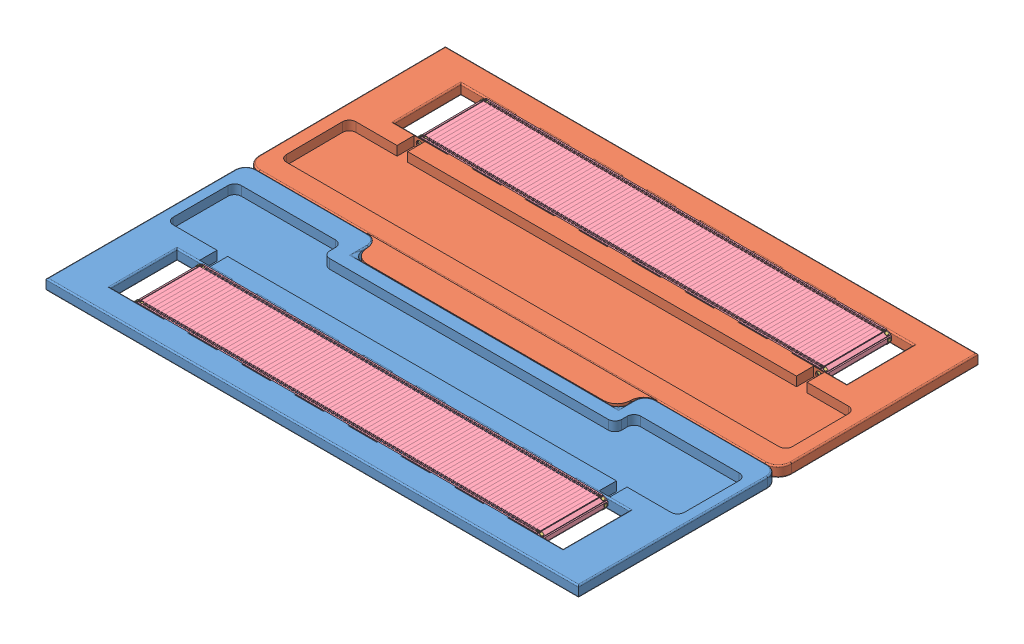
SolidWorks assembly Montagem1, configuration Valor predeterminado. Lengths in mm.
Overall size (400 11.94 300.02).
422 component instances, 5 part files, 18 mates.
Components (placement in the parent):
- LE_robot-1: LE_robot [Valor predeterminado] at (186.3434 129.0951 379.4469) size (400 8.2 150)
- LR_robot-2: LR_robot [Valor predeterminado] at (186.3434 129.6871 229.4211) x (-1 0 0) z (0 0.006964 -0.999976) size (400 8 170)
- Roller-1: Roller [Valor predeterminado] at (36.3434 134.0739 173.885) x (0 -0.006964 0.999976) z (0.000126 0.999976 0.006964) size (58 8 7.93)
- Roller-2: Roller [Valor predeterminado] at (336.3434 134.0739 173.885) x (0 -0.006964 0.999976) z (-0.866025 -0.499989 -0.003482) size (58 8 7.93)
- Roller-3: Roller [Valor predeterminado] at (336.3434 133.0951 435.0122) x (0 0 -1) z (-0.000001 1 0) size (58 8 7.93)
- Roller-4: Roller [Valor predeterminado] at (36.3434 133.0951 435.0122) x (0 0 -1) z (-0.865507 0.500897 0) size (58 8 7.93)
- EsteiraCompleta-1: EsteiraCompleta [Valor predeterminado] at (243.678 123.4337 128.0122) size (307.2 8 50)
  - esteira_caminho1-1: esteira_caminho1 [Valor predeterminado] at (-207.3346 9.6614 308)
  - esteira_borracha1-1: esteira_borracha1 [Valor predeterminado] at (89.6654 12.6614 308) size (3 1 50)
  - esteira_borracha1-9: esteira_borracha1 [Valor predeterminado] at (92.6654 12.6614 308) x (0.866026 -0.499999 0) z (0 0 1) size (3 1 50)
  - esteira_borracha1-10: esteira_borracha1 [Valor predeterminado] at (95.2635 11.1614 308) x (0.000001 -1 0) z (0 0 1) size (3 1 50)
  - esteira_borracha1-11: esteira_borracha1 [Valor predeterminado] at (95.2635 8.1614 308) x (-0.866025 -0.500001 0) z (0 0 1) size (3 1 50)
  - esteira_borracha1-12: esteira_borracha1 [Valor predeterminado] at (92.6654 6.6614 308) x (-1 0 0) z (0 0 1) size (3 1 50)
  - esteira_borracha1-13: esteira_borracha1 [Valor predeterminado] at (89.6654 6.6614 308) x (-1 0 0) z (0 0 1) size (3 1 50)
  - esteira_borracha1-14: esteira_borracha1 [Valor predeterminado] at (86.6654 6.6614 308) x (-1 0 0) z (0 0 1) size (3 1 50)
  - esteira_borracha1-15: esteira_borracha1 [Valor predeterminado] at (83.6654 6.6614 308) x (-1 0 0) z (0 0 1) size (3 1 50)
  - esteira_borracha1-16: esteira_borracha1 [Valor predeterminado] at (80.6654 6.6614 308) x (-1 0 0) z (0 0 1) size (3 1 50)
  - esteira_borracha1-17: esteira_borracha1 [Valor predeterminado] at (77.6654 6.6614 308) x (-1 0 0) z (0 0 1) size (3 1 50)
  - esteira_borracha1-18: esteira_borracha1 [Valor predeterminado] at (74.6654 6.6614 308) x (-1 0 0) z (0 0 1) size (3 1 50)
  - esteira_borracha1-19: esteira_borracha1 [Valor predeterminado] at (71.6654 6.6614 308) x (-1 0 0) z (0 0 1) size (3 1 50)
  - esteira_borracha1-20: esteira_borracha1 [Valor predeterminado] at (68.6654 6.6614 308) x (-1 0 0) z (0 0 1) size (3 1 50)
  - esteira_borracha1-21: esteira_borracha1 [Valor predeterminado] at (65.6654 6.6614 308) x (-1 0 0) z (0 0 1) size (3 1 50)
  - esteira_borracha1-22: esteira_borracha1 [Valor predeterminado] at (62.6654 6.6614 308) x (-1 0 0) z (0 0 1) size (3 1 50)
  - esteira_borracha1-23: esteira_borracha1 [Valor predeterminado] at (59.6654 6.6614 308) x (-1 0 0) z (0 0 1) size (3 1 50)
  - esteira_borracha1-24: esteira_borracha1 [Valor predeterminado] at (56.6654 6.6614 308) x (-1 0 0) z (0 0 1) size (3 1 50)
  - esteira_borracha1-25: esteira_borracha1 [Valor predeterminado] at (53.6654 6.6614 308) x (-1 0 0) z (0 0 1) size (3 1 50)
  - esteira_borracha1-26: esteira_borracha1 [Valor predeterminado] at (50.6654 6.6614 308) x (-1 0 0) z (0 0 1) size (3 1 50)
  - esteira_borracha1-27: esteira_borracha1 [Valor predeterminado] at (47.6654 6.6614 308) x (-1 0 0) z (0 0 1) size (3 1 50)
  - esteira_borracha1-28: esteira_borracha1 [Valor predeterminado] at (44.6653 6.6614 308) x (-1 0 0) z (0 0 1) size (3 1 50)
  - esteira_borracha1-29: esteira_borracha1 [Valor predeterminado] at (41.6653 6.6614 308) x (-1 0 0) z (0 0 1) size (3 1 50)
  - esteira_borracha1-30: esteira_borracha1 [Valor predeterminado] at (38.6653 6.6614 308) x (-1 0 0) z (0 0 1) size (3 1 50)
  - esteira_borracha1-31: esteira_borracha1 [Valor predeterminado] at (35.6653 6.6614 308) x (-1 0 0) z (0 0 1) size (3 1 50)
  - esteira_borracha1-32: esteira_borracha1 [Valor predeterminado] at (32.6653 6.6614 308) x (-1 0 0) z (0 0 1) size (3 1 50)
  - esteira_borracha1-33: esteira_borracha1 [Valor predeterminado] at (29.6653 6.6614 308) x (-1 0 0) z (0 0 1) size (3 1 50)
  - esteira_borracha1-34: esteira_borracha1 [Valor predeterminado] at (26.6653 6.6614 308) x (-1 0 0) z (0 0 1) size (3 1 50)
  - esteira_borracha1-35: esteira_borracha1 [Valor predeterminado] at (23.6653 6.6614 308) x (-1 0 0) z (0 0 1) size (3 1 50)
  - esteira_borracha1-36: esteira_borracha1 [Valor predeterminado] at (20.6653 6.6614 308) x (-1 0 0) z (0 0 1) size (3 1 50)
  - esteira_borracha1-37: esteira_borracha1 [Valor predeterminado] at (17.6653 6.6614 308) x (-1 0 0) z (0 0 1) size (3 1 50)
  - esteira_borracha1-38: esteira_borracha1 [Valor predeterminado] at (14.6653 6.6614 308) x (-1 0 0) z (0 0 1) size (3 1 50)
  - esteira_borracha1-39: esteira_borracha1 [Valor predeterminado] at (11.6653 6.6614 308) x (-1 0 0) z (0 0 1) size (3 1 50)
  - esteira_borracha1-40: esteira_borracha1 [Valor predeterminado] at (8.6653 6.6614 308) x (-1 0 0) z (0 0 1) size (3 1 50)
  - esteira_borracha1-41: esteira_borracha1 [Valor predeterminado] at (5.6653 6.6614 308) x (-1 0 0) z (0 0 1) size (3 1 50)
  - esteira_borracha1-42: esteira_borracha1 [Valor predeterminado] at (2.6653 6.6614 308) x (-1 0 0) z (0 0 1) size (3 1 50)
  - esteira_borracha1-43: esteira_borracha1 [Valor predeterminado] at (-0.3347 6.6614 308) x (-1 0 0) z (0 0 1) size (3 1 50)
  - esteira_borracha1-44: esteira_borracha1 [Valor predeterminado] at (-3.3347 6.6614 308) x (-1 0 0) z (0 0 1) size (3 1 50)
  - esteira_borracha1-45: esteira_borracha1 [Valor predeterminado] at (-6.3347 6.6614 308) x (-1 0 0) z (0 0 1) size (3 1 50)
  - esteira_borracha1-46: esteira_borracha1 [Valor predeterminado] at (-9.3347 6.6614 308) x (-1 0 0) z (0 0 1) size (3 1 50)
  - esteira_borracha1-47: esteira_borracha1 [Valor predeterminado] at (-12.3347 6.6614 308) x (-1 0 0) z (0 0 1) size (3 1 50)
  - esteira_borracha1-48: esteira_borracha1 [Valor predeterminado] at (-15.3347 6.6614 308) x (-1 0 0) z (0 0 1) size (3 1 50)
  - esteira_borracha1-49: esteira_borracha1 [Valor predeterminado] at (-18.3347 6.6614 308) x (-1 0 0) z (0 0 1) size (3 1 50)
  - esteira_borracha1-50: esteira_borracha1 [Valor predeterminado] at (-21.3347 6.6614 308) x (-1 0 0) z (0 0 1) size (3 1 50)
  - esteira_borracha1-51: esteira_borracha1 [Valor predeterminado] at (-24.3347 6.6614 308) x (-1 0 0) z (0 0 1) size (3 1 50)
  - esteira_borracha1-52: esteira_borracha1 [Valor predeterminado] at (-27.3347 6.6614 308) x (-1 0 0) z (0 0 1) size (3 1 50)
  - esteira_borracha1-53: esteira_borracha1 [Valor predeterminado] at (-30.3347 6.6614 308) x (-1 0 0) z (0 0 1) size (3 1 50)
  - esteira_borracha1-54: esteira_borracha1 [Valor predeterminado] at (-33.3348 6.6614 308) x (-1 0 0) z (0 0 1) size (3 1 50)
  - esteira_borracha1-55: esteira_borracha1 [Valor predeterminado] at (-36.3348 6.6614 308) x (-1 0 0) z (0 0 1) size (3 1 50)
  - esteira_borracha1-56: esteira_borracha1 [Valor predeterminado] at (-39.3348 6.6614 308) x (-1 0 0) z (0 0 1) size (3 1 50)
  - esteira_borracha1-57: esteira_borracha1 [Valor predeterminado] at (-42.3348 6.6614 308) x (-1 0 0) z (0 0 1) size (3 1 50)
  - esteira_borracha1-58: esteira_borracha1 [Valor predeterminado] at (-45.3348 6.6614 308) x (-1 0 0) z (0 0 1) size (3 1 50)
  - esteira_borracha1-59: esteira_borracha1 [Valor predeterminado] at (-48.3348 6.6614 308) x (-1 0 0) z (0 0 1) size (3 1 50)
  - esteira_borracha1-60: esteira_borracha1 [Valor predeterminado] at (-51.3348 6.6614 308) x (-1 0 0) z (0 0 1) size (3 1 50)
  - esteira_borracha1-61: esteira_borracha1 [Valor predeterminado] at (-54.3348 6.6614 308) x (-1 0 0) z (0 0 1) size (3 1 50)
  - esteira_borracha1-62: esteira_borracha1 [Valor predeterminado] at (-57.3348 6.6614 308) x (-1 0 0) z (0 0 1) size (3 1 50)
  - esteira_borracha1-63: esteira_borracha1 [Valor predeterminado] at (-60.3348 6.6614 308) x (-1 0 0) z (0 0 1) size (3 1 50)
  - esteira_borracha1-64: esteira_borracha1 [Valor predeterminado] at (-63.3348 6.6614 308) x (-1 0 0) z (0 0 1) size (3 1 50)
  - esteira_borracha1-65: esteira_borracha1 [Valor predeterminado] at (-66.3348 6.6614 308) x (-1 0 0) z (0 0 1) size (3 1 50)
  - esteira_borracha1-66: esteira_borracha1 [Valor predeterminado] at (-69.3348 6.6614 308) x (-1 0 0) z (0 0 1) size (3 1 50)
  - esteira_borracha1-67: esteira_borracha1 [Valor predeterminado] at (-72.3348 6.6614 308) x (-1 0 0) z (0 0 1) size (3 1 50)
  - esteira_borracha1-68: esteira_borracha1 [Valor predeterminado] at (-75.3348 6.6614 308) x (-1 0 0) z (0 0 1) size (3 1 50)
  - esteira_borracha1-69: esteira_borracha1 [Valor predeterminado] at (-78.3348 6.6614 308) x (-1 0 0) z (0 0 1) size (3 1 50)
  - esteira_borracha1-70: esteira_borracha1 [Valor predeterminado] at (-81.3348 6.6614 308) x (-1 0 0) z (0 0 1) size (3 1 50)
  - esteira_borracha1-71: esteira_borracha1 [Valor predeterminado] at (-84.3348 6.6614 308) x (-1 0 0) z (0 0 1) size (3 1 50)
  - esteira_borracha1-72: esteira_borracha1 [Valor predeterminado] at (-87.3348 6.6614 308) x (-1 0 0) z (0 0 1) size (3 1 50)
  - esteira_borracha1-73: esteira_borracha1 [Valor predeterminado] at (-90.3348 6.6614 308) x (-1 0 0) z (0 0 1) size (3 1 50)
  - esteira_borracha1-74: esteira_borracha1 [Valor predeterminado] at (-93.3348 6.6614 308) x (-1 0 0) z (0 0 1) size (3 1 50)
  - esteira_borracha1-75: esteira_borracha1 [Valor predeterminado] at (-96.3348 6.6614 308) x (-1 0 0) z (0 0 1) size (3 1 50)
  - esteira_borracha1-76: esteira_borracha1 [Valor predeterminado] at (-99.3348 6.6614 308) x (-1 0 0) z (0 0 1) size (3 1 50)
  - esteira_borracha1-77: esteira_borracha1 [Valor predeterminado] at (-102.3348 6.6614 308) x (-1 0 0) z (0 0 1) size (3 1 50)
  - esteira_borracha1-78: esteira_borracha1 [Valor predeterminado] at (-105.3348 6.6614 308) x (-1 0 0) z (0 0 1) size (3 1 50)
  - esteira_borracha1-79: esteira_borracha1 [Valor predeterminado] at (-108.3348 6.6614 308) x (-1 0 0) z (0 0 1) size (3 1 50)
  - esteira_borracha1-80: esteira_borracha1 [Valor predeterminado] at (-111.3348 6.6614 308) x (-1 0 0) z (0 0 1) size (3 1 50)
  - esteira_borracha1-81: esteira_borracha1 [Valor predeterminado] at (-114.3349 6.6614 308) x (-1 0 0) z (0 0 1) size (3 1 50)
  - esteira_borracha1-82: esteira_borracha1 [Valor predeterminado] at (-117.3349 6.6614 308) x (-1 0 0) z (0 0 1) size (3 1 50)
  - esteira_borracha1-83: esteira_borracha1 [Valor predeterminado] at (-120.3349 6.6614 308) x (-1 0 0) z (0 0 1) size (3 1 50)
  - esteira_borracha1-84: esteira_borracha1 [Valor predeterminado] at (-123.3349 6.6614 308) x (-1 0 0) z (0 0 1) size (3 1 50)
  - esteira_borracha1-85: esteira_borracha1 [Valor predeterminado] at (-126.3349 6.6614 308) x (-1 0 0) z (0 0 1) size (3 1 50)
  - esteira_borracha1-86: esteira_borracha1 [Valor predeterminado] at (-129.3349 6.6614 308) x (-1 0 0) z (0 0 1) size (3 1 50)
  - esteira_borracha1-87: esteira_borracha1 [Valor predeterminado] at (-132.3349 6.6614 308) x (-1 0 0) z (0 0 1) size (3 1 50)
  - esteira_borracha1-88: esteira_borracha1 [Valor predeterminado] at (-135.3349 6.6614 308) x (-1 0 0) z (0 0 1) size (3 1 50)
  - esteira_borracha1-89: esteira_borracha1 [Valor predeterminado] at (-138.3349 6.6614 308) x (-1 0 0) z (0 0 1) size (3 1 50)
  - esteira_borracha1-90: esteira_borracha1 [Valor predeterminado] at (-141.3349 6.6614 308) x (-1 0 0) z (0 0 1) size (3 1 50)
  - esteira_borracha1-91: esteira_borracha1 [Valor predeterminado] at (-144.3349 6.6614 308) x (-1 0 0) z (0 0 1) size (3 1 50)
  - esteira_borracha1-92: esteira_borracha1 [Valor predeterminado] at (-147.3349 6.6614 308) x (-1 0 0) z (0 0 1) size (3 1 50)
  - esteira_borracha1-93: esteira_borracha1 [Valor predeterminado] at (-150.3349 6.6614 308) x (-1 0 0) z (0 0 1) size (3 1 50)
  - esteira_borracha1-94: esteira_borracha1 [Valor predeterminado] at (-153.3349 6.6614 308) x (-1 0 0) z (0 0 1) size (3 1 50)
  - esteira_borracha1-95: esteira_borracha1 [Valor predeterminado] at (-156.3349 6.6614 308) x (-1 0 0) z (0 0 1) size (3 1 50)
  - esteira_borracha1-96: esteira_borracha1 [Valor predeterminado] at (-159.3349 6.6614 308) x (-1 0 0) z (0 0 1) size (3 1 50)
  - esteira_borracha1-97: esteira_borracha1 [Valor predeterminado] at (-162.3349 6.6614 308) x (-1 0 0) z (0 0 1) size (3 1 50)
  - esteira_borracha1-98: esteira_borracha1 [Valor predeterminado] at (-165.3349 6.6614 308) x (-1 0 0) z (0 0 1) size (3 1 50)
  - esteira_borracha1-99: esteira_borracha1 [Valor predeterminado] at (-168.3349 6.6614 308) x (-1 0 0) z (0 0 1) size (3 1 50)
  - esteira_borracha1-100: esteira_borracha1 [Valor predeterminado] at (-171.3349 6.6614 308) x (-1 0 0) z (0 0 1) size (3 1 50)
  - esteira_borracha1-101: esteira_borracha1 [Valor predeterminado] at (-174.3349 6.6614 308) x (-1 0 0) z (0 0 1) size (3 1 50)
  - esteira_borracha1-102: esteira_borracha1 [Valor predeterminado] at (-177.3349 6.6614 308) x (-1 0 0) z (0 0 1) size (3 1 50)
  - esteira_borracha1-103: esteira_borracha1 [Valor predeterminado] at (-180.3349 6.6614 308) x (-1 0 0) z (0 0 1) size (3 1 50)
  - esteira_borracha1-104: esteira_borracha1 [Valor predeterminado] at (-183.3349 6.6614 308) x (-1 0 0) z (0 0 1) size (3 1 50)
  - esteira_borracha1-105: esteira_borracha1 [Valor predeterminado] at (-186.3349 6.6614 308) x (-1 0 0) z (0 0 1) size (3 1 50)
  - esteira_borracha1-106: esteira_borracha1 [Valor predeterminado] at (-189.3349 6.6614 308) x (-1 0 0) z (0 0 1) size (3 1 50)
  - esteira_borracha1-107: esteira_borracha1 [Valor predeterminado] at (-192.335 6.6614 308) x (-1 0 0) z (0 0 1) size (3 1 50)
  - esteira_borracha1-108: esteira_borracha1 [Valor predeterminado] at (-195.335 6.6614 308) x (-1 0 0) z (0 0 1) size (3 1 50)
  - esteira_borracha1-109: esteira_borracha1 [Valor predeterminado] at (-198.335 6.6614 308) x (-1 0 0) z (0 0 1) size (3 1 50)
  - esteira_borracha1-110: esteira_borracha1 [Valor predeterminado] at (-201.335 6.6614 308) x (-1 0 0) z (0 0 1) size (3 1 50)
  - esteira_borracha1-111: esteira_borracha1 [Valor predeterminado] at (-204.335 6.6614 308) x (-1 0 0) z (0 0 1) size (3 1 50)
  - esteira_borracha1-112: esteira_borracha1 [Valor predeterminado] at (-207.335 6.6614 308) x (-0.865963 0.500107 0) z (0 0 1) size (3 1 50)
  - esteira_borracha1-113: esteira_borracha1 [Valor predeterminado] at (-209.9329 8.1617 308) x (0.000125 1 0) z (0 0 1) size (3 1 50)
  - esteira_borracha1-114: esteira_borracha1 [Valor predeterminado] at (-209.9325 11.1617 308) x (0.866089 0.499891 0) z (0 0 1) size (3 1 50)
  - esteira_borracha1-115: esteira_borracha1 [Valor predeterminado] at (-207.3342 12.6614 308) size (3 1 50)
  - esteira_borracha1-116: esteira_borracha1 [Valor predeterminado] at (-204.3342 12.6614 308) size (3 1 50)
  - esteira_borracha1-117: esteira_borracha1 [Valor predeterminado] at (-201.3342 12.6614 308) size (3 1 50)
  - esteira_borracha1-118: esteira_borracha1 [Valor predeterminado] at (-198.3342 12.6614 308) size (3 1 50)
  - esteira_borracha1-119: esteira_borracha1 [Valor predeterminado] at (-195.3342 12.6614 308) size (3 1 50)
  - esteira_borracha1-120: esteira_borracha1 [Valor predeterminado] at (-192.3342 12.6614 308) size (3 1 50)
  - esteira_borracha1-121: esteira_borracha1 [Valor predeterminado] at (-189.3342 12.6614 308) size (3 1 50)
  - esteira_borracha1-122: esteira_borracha1 [Valor predeterminado] at (-186.3342 12.6614 308) size (3 1 50)
  - esteira_borracha1-123: esteira_borracha1 [Valor predeterminado] at (-183.3342 12.6614 308) size (3 1 50)
  - esteira_borracha1-124: esteira_borracha1 [Valor predeterminado] at (-180.3342 12.6614 308) size (3 1 50)
  - esteira_borracha1-125: esteira_borracha1 [Valor predeterminado] at (-177.3342 12.6614 308) size (3 1 50)
  - esteira_borracha1-126: esteira_borracha1 [Valor predeterminado] at (-174.3342 12.6614 308) size (3 1 50)
  - esteira_borracha1-127: esteira_borracha1 [Valor predeterminado] at (-171.3342 12.6614 308) size (3 1 50)
  - esteira_borracha1-128: esteira_borracha1 [Valor predeterminado] at (-168.3342 12.6614 308) size (3 1 50)
  - esteira_borracha1-129: esteira_borracha1 [Valor predeterminado] at (-165.3342 12.6614 308) size (3 1 50)
  - esteira_borracha1-130: esteira_borracha1 [Valor predeterminado] at (-162.3342 12.6614 308) size (3 1 50)
  - esteira_borracha1-131: esteira_borracha1 [Valor predeterminado] at (-159.3342 12.6614 308) size (3 1 50)
  - esteira_borracha1-132: esteira_borracha1 [Valor predeterminado] at (-156.3342 12.6614 308) size (3 1 50)
  - esteira_borracha1-133: esteira_borracha1 [Valor predeterminado] at (-153.3341 12.6614 308) size (3 1 50)
  - esteira_borracha1-134: esteira_borracha1 [Valor predeterminado] at (-150.3341 12.6614 308) size (3 1 50)
  - esteira_borracha1-135: esteira_borracha1 [Valor predeterminado] at (-147.3341 12.6614 308) size (3 1 50)
  - esteira_borracha1-136: esteira_borracha1 [Valor predeterminado] at (-144.3341 12.6614 308) size (3 1 50)
  - esteira_borracha1-137: esteira_borracha1 [Valor predeterminado] at (-141.3341 12.6614 308) size (3 1 50)
  - esteira_borracha1-138: esteira_borracha1 [Valor predeterminado] at (-138.3341 12.6614 308) size (3 1 50)
  - esteira_borracha1-139: esteira_borracha1 [Valor predeterminado] at (-135.3341 12.6614 308) size (3 1 50)
  - esteira_borracha1-140: esteira_borracha1 [Valor predeterminado] at (-132.3341 12.6614 308) size (3 1 50)
  - esteira_borracha1-141: esteira_borracha1 [Valor predeterminado] at (-129.3341 12.6614 308) size (3 1 50)
  - esteira_borracha1-142: esteira_borracha1 [Valor predeterminado] at (-126.3341 12.6614 308) size (3 1 50)
  - esteira_borracha1-143: esteira_borracha1 [Valor predeterminado] at (-123.3341 12.6614 308) size (3 1 50)
  - esteira_borracha1-144: esteira_borracha1 [Valor predeterminado] at (-120.3341 12.6614 308) size (3 1 50)
  - esteira_borracha1-145: esteira_borracha1 [Valor predeterminado] at (-117.3341 12.6614 308) size (3 1 50)
  - esteira_borracha1-146: esteira_borracha1 [Valor predeterminado] at (-114.3341 12.6614 308) size (3 1 50)
  - esteira_borracha1-147: esteira_borracha1 [Valor predeterminado] at (-111.3341 12.6614 308) size (3 1 50)
  - esteira_borracha1-148: esteira_borracha1 [Valor predeterminado] at (-108.3341 12.6614 308) size (3 1 50)
  - esteira_borracha1-149: esteira_borracha1 [Valor predeterminado] at (-105.3341 12.6614 308) size (3 1 50)
  - esteira_borracha1-150: esteira_borracha1 [Valor predeterminado] at (-102.3341 12.6614 308) size (3 1 50)
  - esteira_borracha1-151: esteira_borracha1 [Valor predeterminado] at (-99.3341 12.6614 308) size (3 1 50)
  - esteira_borracha1-152: esteira_borracha1 [Valor predeterminado] at (-96.3341 12.6614 308) size (3 1 50)
  - esteira_borracha1-153: esteira_borracha1 [Valor predeterminado] at (-93.3341 12.6614 308) size (3 1 50)
  - esteira_borracha1-154: esteira_borracha1 [Valor predeterminado] at (-90.3341 12.6614 308) size (3 1 50)
  - esteira_borracha1-155: esteira_borracha1 [Valor predeterminado] at (-87.3341 12.6614 308) size (3 1 50)
  - esteira_borracha1-156: esteira_borracha1 [Valor predeterminado] at (-84.3341 12.6614 308) size (3 1 50)
  - esteira_borracha1-157: esteira_borracha1 [Valor predeterminado] at (-81.3341 12.6614 308) size (3 1 50)
  - esteira_borracha1-158: esteira_borracha1 [Valor predeterminado] at (-78.3341 12.6614 308) size (3 1 50)
  - esteira_borracha1-159: esteira_borracha1 [Valor predeterminado] at (-75.3341 12.6614 308) size (3 1 50)
  - esteira_borracha1-160: esteira_borracha1 [Valor predeterminado] at (-72.334 12.6614 308) size (3 1 50)
  - esteira_borracha1-161: esteira_borracha1 [Valor predeterminado] at (-69.334 12.6614 308) size (3 1 50)
  - esteira_borracha1-164: esteira_borracha1 [Valor predeterminado] at (-66.334 12.6614 308) size (3 1 50)
  - esteira_borracha1-165: esteira_borracha1 [Valor predeterminado] at (-63.334 12.6614 308) size (3 1 50)
  - esteira_borracha1-166: esteira_borracha1 [Valor predeterminado] at (-60.334 12.6614 308) size (3 1 50)
  - esteira_borracha1-167: esteira_borracha1 [Valor predeterminado] at (-57.334 12.6614 308) size (3 1 50)
  - esteira_borracha1-168: esteira_borracha1 [Valor predeterminado] at (-54.334 12.6614 308) size (3 1 50)
  - esteira_borracha1-169: esteira_borracha1 [Valor predeterminado] at (-51.334 12.6614 308) size (3 1 50)
  - esteira_borracha1-170: esteira_borracha1 [Valor predeterminado] at (-48.334 12.6614 308) size (3 1 50)
  - esteira_borracha1-171: esteira_borracha1 [Valor predeterminado] at (-45.334 12.6614 308) size (3 1 50)
  - esteira_borracha1-172: esteira_borracha1 [Valor predeterminado] at (-42.334 12.6614 308) size (3 1 50)
  - esteira_borracha1-173: esteira_borracha1 [Valor predeterminado] at (-39.334 12.6614 308) size (3 1 50)
  - esteira_borracha1-174: esteira_borracha1 [Valor predeterminado] at (-36.334 12.6614 308) size (3 1 50)
  - esteira_borracha1-175: esteira_borracha1 [Valor predeterminado] at (-33.334 12.6614 308) size (3 1 50)
  - esteira_borracha1-176: esteira_borracha1 [Valor predeterminado] at (-30.334 12.6614 308) size (3 1 50)
  - esteira_borracha1-177: esteira_borracha1 [Valor predeterminado] at (-27.334 12.6614 308) size (3 1 50)
  - esteira_borracha1-178: esteira_borracha1 [Valor predeterminado] at (-24.334 12.6614 308) size (3 1 50)
  - esteira_borracha1-179: esteira_borracha1 [Valor predeterminado] at (-21.334 12.6614 308) size (3 1 50)
  - esteira_borracha1-180: esteira_borracha1 [Valor predeterminado] at (-18.334 12.6614 308) size (3 1 50)
  - esteira_borracha1-181: esteira_borracha1 [Valor predeterminado] at (-15.334 12.6614 308) size (3 1 50)
  - esteira_borracha1-182: esteira_borracha1 [Valor predeterminado] at (-12.334 12.6614 308) size (3 1 50)
  - esteira_borracha1-183: esteira_borracha1 [Valor predeterminado] at (-9.334 12.6614 308) size (3 1 50)
  - esteira_borracha1-184: esteira_borracha1 [Valor predeterminado] at (-6.334 12.6614 308) size (3 1 50)
  - esteira_borracha1-185: esteira_borracha1 [Valor predeterminado] at (-3.334 12.6614 308) size (3 1 50)
  - esteira_borracha1-186: esteira_borracha1 [Valor predeterminado] at (-0.334 12.6614 308) size (3 1 50)
  - esteira_borracha1-187: esteira_borracha1 [Valor predeterminado] at (2.666 12.6614 308) size (3 1 50)
  - esteira_borracha1-188: esteira_borracha1 [Valor predeterminado] at (5.6661 12.6614 308) size (3 1 50)
  - esteira_borracha1-189: esteira_borracha1 [Valor predeterminado] at (8.6661 12.6614 308) size (3 1 50)
  - esteira_borracha1-190: esteira_borracha1 [Valor predeterminado] at (11.6661 12.6614 308) size (3 1 50)
  - esteira_borracha1-191: esteira_borracha1 [Valor predeterminado] at (14.6661 12.6614 308) size (3 1 50)
  - esteira_borracha1-192: esteira_borracha1 [Valor predeterminado] at (17.6661 12.6614 308) size (3 1 50)
  - esteira_borracha1-193: esteira_borracha1 [Valor predeterminado] at (20.6661 12.6614 308) size (3 1 50)
  - esteira_borracha1-194: esteira_borracha1 [Valor predeterminado] at (23.6661 12.6614 308) size (3 1 50)
  - esteira_borracha1-195: esteira_borracha1 [Valor predeterminado] at (26.6661 12.6614 308) size (3 1 50)
  - esteira_borracha1-196: esteira_borracha1 [Valor predeterminado] at (29.6661 12.6614 308) size (3 1 50)
  - esteira_borracha1-197: esteira_borracha1 [Valor predeterminado] at (32.6661 12.6614 308) size (3 1 50)
  - esteira_borracha1-198: esteira_borracha1 [Valor predeterminado] at (35.6661 12.6614 308) size (3 1 50)
  - esteira_borracha1-199: esteira_borracha1 [Valor predeterminado] at (38.6661 12.6614 308) size (3 1 50)
  - esteira_borracha1-200: esteira_borracha1 [Valor predeterminado] at (41.6661 12.6614 308) size (3 1 50)
  - esteira_borracha1-201: esteira_borracha1 [Valor predeterminado] at (44.6661 12.6614 308) size (3 1 50)
  - esteira_borracha1-202: esteira_borracha1 [Valor predeterminado] at (47.6661 12.6614 308) size (3 1 50)
  - esteira_borracha1-203: esteira_borracha1 [Valor predeterminado] at (50.6661 12.6614 308) size (3 1 50)
  - esteira_borracha1-204: esteira_borracha1 [Valor predeterminado] at (53.6661 12.6614 308) size (3 1 50)
  - esteira_borracha1-205: esteira_borracha1 [Valor predeterminado] at (56.6661 12.6614 308) size (3 1 50)
  - esteira_borracha1-206: esteira_borracha1 [Valor predeterminado] at (59.6661 12.6614 308) size (3 1 50)
  - esteira_borracha1-207: esteira_borracha1 [Valor predeterminado] at (62.6661 12.6614 308) size (3 1 50)
  - esteira_borracha1-208: esteira_borracha1 [Valor predeterminado] at (65.6661 12.6614 308) size (3 1 50)
  - esteira_borracha1-209: esteira_borracha1 [Valor predeterminado] at (68.6661 12.6614 308) size (3 1 50)
  - esteira_borracha1-210: esteira_borracha1 [Valor predeterminado] at (71.6661 12.6614 308) size (3 1 50)
  - esteira_borracha1-211: esteira_borracha1 [Valor predeterminado] at (74.6661 12.6614 308) size (3 1 50)
  - esteira_borracha1-212: esteira_borracha1 [Valor predeterminado] at (77.6661 12.6614 308) size (3 1 50)
  - esteira_borracha1-213: esteira_borracha1 [Valor predeterminado] at (80.6661 12.6614 308) size (3 1 50)
  - esteira_borracha1-214: esteira_borracha1 [Valor predeterminado] at (83.6661 12.6614 308) size (3 1 50)
  - esteira_borracha1-215: esteira_borracha1 [Valor predeterminado] at (86.6662 12.6614 308) size (3 1 50)
- EsteiraCompleta-2: EsteiraCompleta [Valor predeterminado] at (243.678 126.2164 -85.176) x (1 0 0) z (0 -0.006964 0.999976) size (307.2 8 50)
  - esteira_caminho1-1: esteira_caminho1 [Valor predeterminado] at (-207.3346 9.6614 308)
  - esteira_borracha1-1: esteira_borracha1 [Valor predeterminado] at (89.6654 12.6614 308) size (3 1 50)
  - esteira_borracha1-9: esteira_borracha1 [Valor predeterminado] at (92.6654 12.6614 308) x (0.866026 -0.499999 0) z (0 0 1) size (3 1 50)
  - esteira_borracha1-10: esteira_borracha1 [Valor predeterminado] at (95.2635 11.1614 308) x (0.000001 -1 0) z (0 0 1) size (3 1 50)
  - esteira_borracha1-11: esteira_borracha1 [Valor predeterminado] at (95.2635 8.1614 308) x (-0.866025 -0.500001 0) z (0 0 1) size (3 1 50)
  - esteira_borracha1-12: esteira_borracha1 [Valor predeterminado] at (92.6654 6.6614 308) x (-1 0 0) z (0 0 1) size (3 1 50)
  - esteira_borracha1-13: esteira_borracha1 [Valor predeterminado] at (89.6654 6.6614 308) x (-1 0 0) z (0 0 1) size (3 1 50)
  - esteira_borracha1-14: esteira_borracha1 [Valor predeterminado] at (86.6654 6.6614 308) x (-1 0 0) z (0 0 1) size (3 1 50)
  - esteira_borracha1-15: esteira_borracha1 [Valor predeterminado] at (83.6654 6.6614 308) x (-1 0 0) z (0 0 1) size (3 1 50)
  - esteira_borracha1-16: esteira_borracha1 [Valor predeterminado] at (80.6654 6.6614 308) x (-1 0 0) z (0 0 1) size (3 1 50)
  - esteira_borracha1-17: esteira_borracha1 [Valor predeterminado] at (77.6654 6.6614 308) x (-1 0 0) z (0 0 1) size (3 1 50)
  - esteira_borracha1-18: esteira_borracha1 [Valor predeterminado] at (74.6654 6.6614 308) x (-1 0 0) z (0 0 1) size (3 1 50)
  - esteira_borracha1-19: esteira_borracha1 [Valor predeterminado] at (71.6654 6.6614 308) x (-1 0 0) z (0 0 1) size (3 1 50)
  - esteira_borracha1-20: esteira_borracha1 [Valor predeterminado] at (68.6654 6.6614 308) x (-1 0 0) z (0 0 1) size (3 1 50)
  - esteira_borracha1-21: esteira_borracha1 [Valor predeterminado] at (65.6654 6.6614 308) x (-1 0 0) z (0 0 1) size (3 1 50)
  - esteira_borracha1-22: esteira_borracha1 [Valor predeterminado] at (62.6654 6.6614 308) x (-1 0 0) z (0 0 1) size (3 1 50)
  - esteira_borracha1-23: esteira_borracha1 [Valor predeterminado] at (59.6654 6.6614 308) x (-1 0 0) z (0 0 1) size (3 1 50)
  - esteira_borracha1-24: esteira_borracha1 [Valor predeterminado] at (56.6654 6.6614 308) x (-1 0 0) z (0 0 1) size (3 1 50)
  - esteira_borracha1-25: esteira_borracha1 [Valor predeterminado] at (53.6654 6.6614 308) x (-1 0 0) z (0 0 1) size (3 1 50)
  - esteira_borracha1-26: esteira_borracha1 [Valor predeterminado] at (50.6654 6.6614 308) x (-1 0 0) z (0 0 1) size (3 1 50)
  - esteira_borracha1-27: esteira_borracha1 [Valor predeterminado] at (47.6654 6.6614 308) x (-1 0 0) z (0 0 1) size (3 1 50)
  - esteira_borracha1-28: esteira_borracha1 [Valor predeterminado] at (44.6653 6.6614 308) x (-1 0 0) z (0 0 1) size (3 1 50)
  - esteira_borracha1-29: esteira_borracha1 [Valor predeterminado] at (41.6653 6.6614 308) x (-1 0 0) z (0 0 1) size (3 1 50)
  - esteira_borracha1-30: esteira_borracha1 [Valor predeterminado] at (38.6653 6.6614 308) x (-1 0 0) z (0 0 1) size (3 1 50)
  - esteira_borracha1-31: esteira_borracha1 [Valor predeterminado] at (35.6653 6.6614 308) x (-1 0 0) z (0 0 1) size (3 1 50)
  - esteira_borracha1-32: esteira_borracha1 [Valor predeterminado] at (32.6653 6.6614 308) x (-1 0 0) z (0 0 1) size (3 1 50)
  - esteira_borracha1-33: esteira_borracha1 [Valor predeterminado] at (29.6653 6.6614 308) x (-1 0 0) z (0 0 1) size (3 1 50)
  - esteira_borracha1-34: esteira_borracha1 [Valor predeterminado] at (26.6653 6.6614 308) x (-1 0 0) z (0 0 1) size (3 1 50)
  - esteira_borracha1-35: esteira_borracha1 [Valor predeterminado] at (23.6653 6.6614 308) x (-1 0 0) z (0 0 1) size (3 1 50)
  - esteira_borracha1-36: esteira_borracha1 [Valor predeterminado] at (20.6653 6.6614 308) x (-1 0 0) z (0 0 1) size (3 1 50)
  - esteira_borracha1-37: esteira_borracha1 [Valor predeterminado] at (17.6653 6.6614 308) x (-1 0 0) z (0 0 1) size (3 1 50)
  - esteira_borracha1-38: esteira_borracha1 [Valor predeterminado] at (14.6653 6.6614 308) x (-1 0 0) z (0 0 1) size (3 1 50)
  - esteira_borracha1-39: esteira_borracha1 [Valor predeterminado] at (11.6653 6.6614 308) x (-1 0 0) z (0 0 1) size (3 1 50)
  - esteira_borracha1-40: esteira_borracha1 [Valor predeterminado] at (8.6653 6.6614 308) x (-1 0 0) z (0 0 1) size (3 1 50)
  - esteira_borracha1-41: esteira_borracha1 [Valor predeterminado] at (5.6653 6.6614 308) x (-1 0 0) z (0 0 1) size (3 1 50)
  - esteira_borracha1-42: esteira_borracha1 [Valor predeterminado] at (2.6653 6.6614 308) x (-1 0 0) z (0 0 1) size (3 1 50)
  - esteira_borracha1-43: esteira_borracha1 [Valor predeterminado] at (-0.3347 6.6614 308) x (-1 0 0) z (0 0 1) size (3 1 50)
  - esteira_borracha1-44: esteira_borracha1 [Valor predeterminado] at (-3.3347 6.6614 308) x (-1 0 0) z (0 0 1) size (3 1 50)
  - esteira_borracha1-45: esteira_borracha1 [Valor predeterminado] at (-6.3347 6.6614 308) x (-1 0 0) z (0 0 1) size (3 1 50)
  - esteira_borracha1-46: esteira_borracha1 [Valor predeterminado] at (-9.3347 6.6614 308) x (-1 0 0) z (0 0 1) size (3 1 50)
  - esteira_borracha1-47: esteira_borracha1 [Valor predeterminado] at (-12.3347 6.6614 308) x (-1 0 0) z (0 0 1) size (3 1 50)
  - esteira_borracha1-48: esteira_borracha1 [Valor predeterminado] at (-15.3347 6.6614 308) x (-1 0 0) z (0 0 1) size (3 1 50)
  - esteira_borracha1-49: esteira_borracha1 [Valor predeterminado] at (-18.3347 6.6614 308) x (-1 0 0) z (0 0 1) size (3 1 50)
  - esteira_borracha1-50: esteira_borracha1 [Valor predeterminado] at (-21.3347 6.6614 308) x (-1 0 0) z (0 0 1) size (3 1 50)
  - esteira_borracha1-51: esteira_borracha1 [Valor predeterminado] at (-24.3347 6.6614 308) x (-1 0 0) z (0 0 1) size (3 1 50)
  - esteira_borracha1-52: esteira_borracha1 [Valor predeterminado] at (-27.3347 6.6614 308) x (-1 0 0) z (0 0 1) size (3 1 50)
  - esteira_borracha1-53: esteira_borracha1 [Valor predeterminado] at (-30.3347 6.6614 308) x (-1 0 0) z (0 0 1) size (3 1 50)
  - esteira_borracha1-54: esteira_borracha1 [Valor predeterminado] at (-33.3348 6.6614 308) x (-1 0 0) z (0 0 1) size (3 1 50)
  - esteira_borracha1-55: esteira_borracha1 [Valor predeterminado] at (-36.3348 6.6614 308) x (-1 0 0) z (0 0 1) size (3 1 50)
  - esteira_borracha1-56: esteira_borracha1 [Valor predeterminado] at (-39.3348 6.6614 308) x (-1 0 0) z (0 0 1) size (3 1 50)
  - esteira_borracha1-57: esteira_borracha1 [Valor predeterminado] at (-42.3348 6.6614 308) x (-1 0 0) z (0 0 1) size (3 1 50)
  - esteira_borracha1-58: esteira_borracha1 [Valor predeterminado] at (-45.3348 6.6614 308) x (-1 0 0) z (0 0 1) size (3 1 50)
  - esteira_borracha1-59: esteira_borracha1 [Valor predeterminado] at (-48.3348 6.6614 308) x (-1 0 0) z (0 0 1) size (3 1 50)
  - esteira_borracha1-60: esteira_borracha1 [Valor predeterminado] at (-51.3348 6.6614 308) x (-1 0 0) z (0 0 1) size (3 1 50)
  - esteira_borracha1-61: esteira_borracha1 [Valor predeterminado] at (-54.3348 6.6614 308) x (-1 0 0) z (0 0 1) size (3 1 50)
  - esteira_borracha1-62: esteira_borracha1 [Valor predeterminado] at (-57.3348 6.6614 308) x (-1 0 0) z (0 0 1) size (3 1 50)
  - esteira_borracha1-63: esteira_borracha1 [Valor predeterminado] at (-60.3348 6.6614 308) x (-1 0 0) z (0 0 1) size (3 1 50)
  - esteira_borracha1-64: esteira_borracha1 [Valor predeterminado] at (-63.3348 6.6614 308) x (-1 0 0) z (0 0 1) size (3 1 50)
  - esteira_borracha1-65: esteira_borracha1 [Valor predeterminado] at (-66.3348 6.6614 308) x (-1 0 0) z (0 0 1) size (3 1 50)
  - esteira_borracha1-66: esteira_borracha1 [Valor predeterminado] at (-69.3348 6.6614 308) x (-1 0 0) z (0 0 1) size (3 1 50)
  - esteira_borracha1-67: esteira_borracha1 [Valor predeterminado] at (-72.3348 6.6614 308) x (-1 0 0) z (0 0 1) size (3 1 50)
  - esteira_borracha1-68: esteira_borracha1 [Valor predeterminado] at (-75.3348 6.6614 308) x (-1 0 0) z (0 0 1) size (3 1 50)
  - esteira_borracha1-69: esteira_borracha1 [Valor predeterminado] at (-78.3348 6.6614 308) x (-1 0 0) z (0 0 1) size (3 1 50)
  - esteira_borracha1-70: esteira_borracha1 [Valor predeterminado] at (-81.3348 6.6614 308) x (-1 0 0) z (0 0 1) size (3 1 50)
  - esteira_borracha1-71: esteira_borracha1 [Valor predeterminado] at (-84.3348 6.6614 308) x (-1 0 0) z (0 0 1) size (3 1 50)
  - esteira_borracha1-72: esteira_borracha1 [Valor predeterminado] at (-87.3348 6.6614 308) x (-1 0 0) z (0 0 1) size (3 1 50)
  - esteira_borracha1-73: esteira_borracha1 [Valor predeterminado] at (-90.3348 6.6614 308) x (-1 0 0) z (0 0 1) size (3 1 50)
  - esteira_borracha1-74: esteira_borracha1 [Valor predeterminado] at (-93.3348 6.6614 308) x (-1 0 0) z (0 0 1) size (3 1 50)
  - esteira_borracha1-75: esteira_borracha1 [Valor predeterminado] at (-96.3348 6.6614 308) x (-1 0 0) z (0 0 1) size (3 1 50)
  - esteira_borracha1-76: esteira_borracha1 [Valor predeterminado] at (-99.3348 6.6614 308) x (-1 0 0) z (0 0 1) size (3 1 50)
  - esteira_borracha1-77: esteira_borracha1 [Valor predeterminado] at (-102.3348 6.6614 308) x (-1 0 0) z (0 0 1) size (3 1 50)
  - esteira_borracha1-78: esteira_borracha1 [Valor predeterminado] at (-105.3348 6.6614 308) x (-1 0 0) z (0 0 1) size (3 1 50)
  - esteira_borracha1-79: esteira_borracha1 [Valor predeterminado] at (-108.3348 6.6614 308) x (-1 0 0) z (0 0 1) size (3 1 50)
  - esteira_borracha1-80: esteira_borracha1 [Valor predeterminado] at (-111.3348 6.6614 308) x (-1 0 0) z (0 0 1) size (3 1 50)
  - esteira_borracha1-81: esteira_borracha1 [Valor predeterminado] at (-114.3349 6.6614 308) x (-1 0 0) z (0 0 1) size (3 1 50)
  - esteira_borracha1-82: esteira_borracha1 [Valor predeterminado] at (-117.3349 6.6614 308) x (-1 0 0) z (0 0 1) size (3 1 50)
  - esteira_borracha1-83: esteira_borracha1 [Valor predeterminado] at (-120.3349 6.6614 308) x (-1 0 0) z (0 0 1) size (3 1 50)
  - esteira_borracha1-84: esteira_borracha1 [Valor predeterminado] at (-123.3349 6.6614 308) x (-1 0 0) z (0 0 1) size (3 1 50)
  - esteira_borracha1-85: esteira_borracha1 [Valor predeterminado] at (-126.3349 6.6614 308) x (-1 0 0) z (0 0 1) size (3 1 50)
  - esteira_borracha1-86: esteira_borracha1 [Valor predeterminado] at (-129.3349 6.6614 308) x (-1 0 0) z (0 0 1) size (3 1 50)
  - esteira_borracha1-87: esteira_borracha1 [Valor predeterminado] at (-132.3349 6.6614 308) x (-1 0 0) z (0 0 1) size (3 1 50)
  - esteira_borracha1-88: esteira_borracha1 [Valor predeterminado] at (-135.3349 6.6614 308) x (-1 0 0) z (0 0 1) size (3 1 50)
  - esteira_borracha1-89: esteira_borracha1 [Valor predeterminado] at (-138.3349 6.6614 308) x (-1 0 0) z (0 0 1) size (3 1 50)
  - esteira_borracha1-90: esteira_borracha1 [Valor predeterminado] at (-141.3349 6.6614 308) x (-1 0 0) z (0 0 1) size (3 1 50)
  - esteira_borracha1-91: esteira_borracha1 [Valor predeterminado] at (-144.3349 6.6614 308) x (-1 0 0) z (0 0 1) size (3 1 50)
  - esteira_borracha1-92: esteira_borracha1 [Valor predeterminado] at (-147.3349 6.6614 308) x (-1 0 0) z (0 0 1) size (3 1 50)
  - esteira_borracha1-93: esteira_borracha1 [Valor predeterminado] at (-150.3349 6.6614 308) x (-1 0 0) z (0 0 1) size (3 1 50)
  - esteira_borracha1-94: esteira_borracha1 [Valor predeterminado] at (-153.3349 6.6614 308) x (-1 0 0) z (0 0 1) size (3 1 50)
  - esteira_borracha1-95: esteira_borracha1 [Valor predeterminado] at (-156.3349 6.6614 308) x (-1 0 0) z (0 0 1) size (3 1 50)
  - esteira_borracha1-96: esteira_borracha1 [Valor predeterminado] at (-159.3349 6.6614 308) x (-1 0 0) z (0 0 1) size (3 1 50)
  - esteira_borracha1-97: esteira_borracha1 [Valor predeterminado] at (-162.3349 6.6614 308) x (-1 0 0) z (0 0 1) size (3 1 50)
  - esteira_borracha1-98: esteira_borracha1 [Valor predeterminado] at (-165.3349 6.6614 308) x (-1 0 0) z (0 0 1) size (3 1 50)
  - esteira_borracha1-99: esteira_borracha1 [Valor predeterminado] at (-168.3349 6.6614 308) x (-1 0 0) z (0 0 1) size (3 1 50)
  - esteira_borracha1-100: esteira_borracha1 [Valor predeterminado] at (-171.3349 6.6614 308) x (-1 0 0) z (0 0 1) size (3 1 50)
  - esteira_borracha1-101: esteira_borracha1 [Valor predeterminado] at (-174.3349 6.6614 308) x (-1 0 0) z (0 0 1) size (3 1 50)
  - esteira_borracha1-102: esteira_borracha1 [Valor predeterminado] at (-177.3349 6.6614 308) x (-1 0 0) z (0 0 1) size (3 1 50)
  - esteira_borracha1-103: esteira_borracha1 [Valor predeterminado] at (-180.3349 6.6614 308) x (-1 0 0) z (0 0 1) size (3 1 50)
  - esteira_borracha1-104: esteira_borracha1 [Valor predeterminado] at (-183.3349 6.6614 308) x (-1 0 0) z (0 0 1) size (3 1 50)
  - esteira_borracha1-105: esteira_borracha1 [Valor predeterminado] at (-186.3349 6.6614 308) x (-1 0 0) z (0 0 1) size (3 1 50)
  - esteira_borracha1-106: esteira_borracha1 [Valor predeterminado] at (-189.3349 6.6614 308) x (-1 0 0) z (0 0 1) size (3 1 50)
  - esteira_borracha1-107: esteira_borracha1 [Valor predeterminado] at (-192.335 6.6614 308) x (-1 0 0) z (0 0 1) size (3 1 50)
  - esteira_borracha1-108: esteira_borracha1 [Valor predeterminado] at (-195.335 6.6614 308) x (-1 0 0) z (0 0 1) size (3 1 50)
  - esteira_borracha1-109: esteira_borracha1 [Valor predeterminado] at (-198.335 6.6614 308) x (-1 0 0) z (0 0 1) size (3 1 50)
  - esteira_borracha1-110: esteira_borracha1 [Valor predeterminado] at (-201.335 6.6614 308) x (-1 0 0) z (0 0 1) size (3 1 50)
  - esteira_borracha1-111: esteira_borracha1 [Valor predeterminado] at (-204.335 6.6614 308) x (-1 0 0) z (0 0 1) size (3 1 50)
  - esteira_borracha1-112: esteira_borracha1 [Valor predeterminado] at (-207.335 6.6614 308) x (-0.865963 0.500107 0) z (0 0 1) size (3 1 50)
  - esteira_borracha1-113: esteira_borracha1 [Valor predeterminado] at (-209.9329 8.1617 308) x (0.000125 1 0) z (0 0 1) size (3 1 50)
  - esteira_borracha1-114: esteira_borracha1 [Valor predeterminado] at (-209.9325 11.1617 308) x (0.866089 0.499891 0) z (0 0 1) size (3 1 50)
  - esteira_borracha1-115: esteira_borracha1 [Valor predeterminado] at (-207.3342 12.6614 308) size (3 1 50)
  - esteira_borracha1-116: esteira_borracha1 [Valor predeterminado] at (-204.3342 12.6614 308) size (3 1 50)
  - esteira_borracha1-117: esteira_borracha1 [Valor predeterminado] at (-201.3342 12.6614 308) size (3 1 50)
  - esteira_borracha1-118: esteira_borracha1 [Valor predeterminado] at (-198.3342 12.6614 308) size (3 1 50)
  - esteira_borracha1-119: esteira_borracha1 [Valor predeterminado] at (-195.3342 12.6614 308) size (3 1 50)
  - esteira_borracha1-120: esteira_borracha1 [Valor predeterminado] at (-192.3342 12.6614 308) size (3 1 50)
  - esteira_borracha1-121: esteira_borracha1 [Valor predeterminado] at (-189.3342 12.6614 308) size (3 1 50)
  - esteira_borracha1-122: esteira_borracha1 [Valor predeterminado] at (-186.3342 12.6614 308) size (3 1 50)
  - esteira_borracha1-123: esteira_borracha1 [Valor predeterminado] at (-183.3342 12.6614 308) size (3 1 50)
  - esteira_borracha1-124: esteira_borracha1 [Valor predeterminado] at (-180.3342 12.6614 308) size (3 1 50)
  - esteira_borracha1-125: esteira_borracha1 [Valor predeterminado] at (-177.3342 12.6614 308) size (3 1 50)
  - esteira_borracha1-126: esteira_borracha1 [Valor predeterminado] at (-174.3342 12.6614 308) size (3 1 50)
  - esteira_borracha1-127: esteira_borracha1 [Valor predeterminado] at (-171.3342 12.6614 308) size (3 1 50)
  - esteira_borracha1-128: esteira_borracha1 [Valor predeterminado] at (-168.3342 12.6614 308) size (3 1 50)
  - esteira_borracha1-129: esteira_borracha1 [Valor predeterminado] at (-165.3342 12.6614 308) size (3 1 50)
  - esteira_borracha1-130: esteira_borracha1 [Valor predeterminado] at (-162.3342 12.6614 308) size (3 1 50)
  - esteira_borracha1-131: esteira_borracha1 [Valor predeterminado] at (-159.3342 12.6614 308) size (3 1 50)
  - esteira_borracha1-132: esteira_borracha1 [Valor predeterminado] at (-156.3342 12.6614 308) size (3 1 50)
  - esteira_borracha1-133: esteira_borracha1 [Valor predeterminado] at (-153.3341 12.6614 308) size (3 1 50)
  - esteira_borracha1-134: esteira_borracha1 [Valor predeterminado] at (-150.3341 12.6614 308) size (3 1 50)
  - esteira_borracha1-135: esteira_borracha1 [Valor predeterminado] at (-147.3341 12.6614 308) size (3 1 50)
  - esteira_borracha1-136: esteira_borracha1 [Valor predeterminado] at (-144.3341 12.6614 308) size (3 1 50)
  - esteira_borracha1-137: esteira_borracha1 [Valor predeterminado] at (-141.3341 12.6614 308) size (3 1 50)
  - esteira_borracha1-138: esteira_borracha1 [Valor predeterminado] at (-138.3341 12.6614 308) size (3 1 50)
  - esteira_borracha1-139: esteira_borracha1 [Valor predeterminado] at (-135.3341 12.6614 308) size (3 1 50)
  - esteira_borracha1-140: esteira_borracha1 [Valor predeterminado] at (-132.3341 12.6614 308) size (3 1 50)
  - esteira_borracha1-141: esteira_borracha1 [Valor predeterminado] at (-129.3341 12.6614 308) size (3 1 50)
  - esteira_borracha1-142: esteira_borracha1 [Valor predeterminado] at (-126.3341 12.6614 308) size (3 1 50)
  - esteira_borracha1-143: esteira_borracha1 [Valor predeterminado] at (-123.3341 12.6614 308) size (3 1 50)
  - esteira_borracha1-144: esteira_borracha1 [Valor predeterminado] at (-120.3341 12.6614 308) size (3 1 50)
  - esteira_borracha1-145: esteira_borracha1 [Valor predeterminado] at (-117.3341 12.6614 308) size (3 1 50)
  - esteira_borracha1-146: esteira_borracha1 [Valor predeterminado] at (-114.3341 12.6614 308) size (3 1 50)
  - esteira_borracha1-147: esteira_borracha1 [Valor predeterminado] at (-111.3341 12.6614 308) size (3 1 50)
  - esteira_borracha1-148: esteira_borracha1 [Valor predeterminado] at (-108.3341 12.6614 308) size (3 1 50)
  - esteira_borracha1-149: esteira_borracha1 [Valor predeterminado] at (-105.3341 12.6614 308) size (3 1 50)
  - esteira_borracha1-150: esteira_borracha1 [Valor predeterminado] at (-102.3341 12.6614 308) size (3 1 50)
  - esteira_borracha1-151: esteira_borracha1 [Valor predeterminado] at (-99.3341 12.6614 308) size (3 1 50)
  - esteira_borracha1-152: esteira_borracha1 [Valor predeterminado] at (-96.3341 12.6614 308) size (3 1 50)
  - esteira_borracha1-153: esteira_borracha1 [Valor predeterminado] at (-93.3341 12.6614 308) size (3 1 50)
  - esteira_borracha1-154: esteira_borracha1 [Valor predeterminado] at (-90.3341 12.6614 308) size (3 1 50)
  - esteira_borracha1-155: esteira_borracha1 [Valor predeterminado] at (-87.3341 12.6614 308) size (3 1 50)
  - esteira_borracha1-156: esteira_borracha1 [Valor predeterminado] at (-84.3341 12.6614 308) size (3 1 50)
  - esteira_borracha1-157: esteira_borracha1 [Valor predeterminado] at (-81.3341 12.6614 308) size (3 1 50)
  - esteira_borracha1-158: esteira_borracha1 [Valor predeterminado] at (-78.3341 12.6614 308) size (3 1 50)
  - esteira_borracha1-159: esteira_borracha1 [Valor predeterminado] at (-75.3341 12.6614 308) size (3 1 50)
  - esteira_borracha1-160: esteira_borracha1 [Valor predeterminado] at (-72.334 12.6614 308) size (3 1 50)
  - esteira_borracha1-161: esteira_borracha1 [Valor predeterminado] at (-69.334 12.6614 308) size (3 1 50)
  - esteira_borracha1-164: esteira_borracha1 [Valor predeterminado] at (-66.334 12.6614 308) size (3 1 50)
  - esteira_borracha1-165: esteira_borracha1 [Valor predeterminado] at (-63.334 12.6614 308) size (3 1 50)
  - esteira_borracha1-166: esteira_borracha1 [Valor predeterminado] at (-60.334 12.6614 308) size (3 1 50)
  - esteira_borracha1-167: esteira_borracha1 [Valor predeterminado] at (-57.334 12.6614 308) size (3 1 50)
  - esteira_borracha1-168: esteira_borracha1 [Valor predeterminado] at (-54.334 12.6614 308) size (3 1 50)
  - esteira_borracha1-169: esteira_borracha1 [Valor predeterminado] at (-51.334 12.6614 308) size (3 1 50)
  - esteira_borracha1-170: esteira_borracha1 [Valor predeterminado] at (-48.334 12.6614 308) size (3 1 50)
  - esteira_borracha1-171: esteira_borracha1 [Valor predeterminado] at (-45.334 12.6614 308) size (3 1 50)
  - esteira_borracha1-172: esteira_borracha1 [Valor predeterminado] at (-42.334 12.6614 308) size (3 1 50)
  - esteira_borracha1-173: esteira_borracha1 [Valor predeterminado] at (-39.334 12.6614 308) size (3 1 50)
  - esteira_borracha1-174: esteira_borracha1 [Valor predeterminado] at (-36.334 12.6614 308) size (3 1 50)
  - esteira_borracha1-175: esteira_borracha1 [Valor predeterminado] at (-33.334 12.6614 308) size (3 1 50)
  - esteira_borracha1-176: esteira_borracha1 [Valor predeterminado] at (-30.334 12.6614 308) size (3 1 50)
  - esteira_borracha1-177: esteira_borracha1 [Valor predeterminado] at (-27.334 12.6614 308) size (3 1 50)
  - esteira_borracha1-178: esteira_borracha1 [Valor predeterminado] at (-24.334 12.6614 308) size (3 1 50)
  - esteira_borracha1-179: esteira_borracha1 [Valor predeterminado] at (-21.334 12.6614 308) size (3 1 50)
  - esteira_borracha1-180: esteira_borracha1 [Valor predeterminado] at (-18.334 12.6614 308) size (3 1 50)
  - esteira_borracha1-181: esteira_borracha1 [Valor predeterminado] at (-15.334 12.6614 308) size (3 1 50)
  - esteira_borracha1-182: esteira_borracha1 [Valor predeterminado] at (-12.334 12.6614 308) size (3 1 50)
  - esteira_borracha1-183: esteira_borracha1 [Valor predeterminado] at (-9.334 12.6614 308) size (3 1 50)
  - esteira_borracha1-184: esteira_borracha1 [Valor predeterminado] at (-6.334 12.6614 308) size (3 1 50)
  - esteira_borracha1-185: esteira_borracha1 [Valor predeterminado] at (-3.334 12.6614 308) size (3 1 50)
  - esteira_borracha1-186: esteira_borracha1 [Valor predeterminado] at (-0.334 12.6614 308) size (3 1 50)
  - esteira_borracha1-187: esteira_borracha1 [Valor predeterminado] at (2.666 12.6614 308) size (3 1 50)
  - esteira_borracha1-188: esteira_borracha1 [Valor predeterminado] at (5.6661 12.6614 308) size (3 1 50)
  - esteira_borracha1-189: esteira_borracha1 [Valor predeterminado] at (8.6661 12.6614 308) size (3 1 50)
  - esteira_borracha1-190: esteira_borracha1 [Valor predeterminado] at (11.6661 12.6614 308) size (3 1 50)
  - esteira_borracha1-191: esteira_borracha1 [Valor predeterminado] at (14.6661 12.6614 308) size (3 1 50)
  - esteira_borracha1-192: esteira_borracha1 [Valor predeterminado] at (17.6661 12.6614 308) size (3 1 50)
  - esteira_borracha1-193: esteira_borracha1 [Valor predeterminado] at (20.6661 12.6614 308) size (3 1 50)
  - esteira_borracha1-194: esteira_borracha1 [Valor predeterminado] at (23.6661 12.6614 308) size (3 1 50)
  - esteira_borracha1-195: esteira_borracha1 [Valor predeterminado] at (26.6661 12.6614 308) size (3 1 50)
  - esteira_borracha1-196: esteira_borracha1 [Valor predeterminado] at (29.6661 12.6614 308) size (3 1 50)
  - esteira_borracha1-197: esteira_borracha1 [Valor predeterminado] at (32.6661 12.6614 308) size (3 1 50)
  - esteira_borracha1-198: esteira_borracha1 [Valor predeterminado] at (35.6661 12.6614 308) size (3 1 50)
  - esteira_borracha1-199: esteira_borracha1 [Valor predeterminado] at (38.6661 12.6614 308) size (3 1 50)
  - esteira_borracha1-200: esteira_borracha1 [Valor predeterminado] at (41.6661 12.6614 308) size (3 1 50)
  - esteira_borracha1-201: esteira_borracha1 [Valor predeterminado] at (44.6661 12.6614 308) size (3 1 50)
  - esteira_borracha1-202: esteira_borracha1 [Valor predeterminado] at (47.6661 12.6614 308) size (3 1 50)
  - esteira_borracha1-203: esteira_borracha1 [Valor predeterminado] at (50.6661 12.6614 308) size (3 1 50)
  - esteira_borracha1-204: esteira_borracha1 [Valor predeterminado] at (53.6661 12.6614 308) size (3 1 50)
  - esteira_borracha1-205: esteira_borracha1 [Valor predeterminado] at (56.6661 12.6614 308) size (3 1 50)
  - esteira_borracha1-206: esteira_borracha1 [Valor predeterminado] at (59.6661 12.6614 308) size (3 1 50)
  - esteira_borracha1-207: esteira_borracha1 [Valor predeterminado] at (62.6661 12.6614 308) size (3 1 50)
  - esteira_borracha1-208: esteira_borracha1 [Valor predeterminado] at (65.6661 12.6614 308) size (3 1 50)
  - esteira_borracha1-209: esteira_borracha1 [Valor predeterminado] at (68.6661 12.6614 308) size (3 1 50)
  - esteira_borracha1-210: esteira_borracha1 [Valor predeterminado] at (71.6661 12.6614 308) size (3 1 50)
  - esteira_borracha1-211: esteira_borracha1 [Valor predeterminado] at (74.6661 12.6614 308) size (3 1 50)
  - esteira_borracha1-212: esteira_borracha1 [Valor predeterminado] at (77.6661 12.6614 308) size (3 1 50)
  - esteira_borracha1-213: esteira_borracha1 [Valor predeterminado] at (80.6661 12.6614 308) size (3 1 50)
  - esteira_borracha1-214: esteira_borracha1 [Valor predeterminado] at (83.6661 12.6614 308) size (3 1 50)
  - esteira_borracha1-215: esteira_borracha1 [Valor predeterminado] at (86.6662 12.6614 308) size (3 1 50)
Mates (geometry in assembly coordinates):
- Concêntrico2: concentric: cylinder of assembly; cylinder of assembly; cylinder of LE_robot-1 through (296.3434 133.0951 314.4469) axis (-1 0 0) radius 3.25; cylinder of LR_robot-2 through (294.3434 133.0951 314.4469) axis (-1 0 0) radius 3
- Distância4: distance = 1 mm: plane of assembly; plane of assembly; plane of LR_robot-2 through (97.3434 133.0951 314.4469) normal (-1 0 0); plane of LE_robot-1 through (96.3434 133.0951 314.4469) normal (1 0 0)
- Distância5: distance = 1 mm: plane of assembly; plane of assembly; plane of LR_robot-2 through (16.3434 129.7328 222.856) normal (0 0.006964 -0.999976); plane of Roller-1 through (36.3434 133.7397 221.8839) normal (0 -0.006964 0.999976)
- Concêntrico3: concentric: circle of assembly; circle of assembly; circle of LR_robot-2; circle of Roller-1
- Distância6: distance = 1 mm: plane of assembly; plane of assembly; plane of LR_robot-2 through (16.3434 129.7328 222.856) normal (0 0.006964 -0.999976); plane of Roller-2 through (336.3434 133.7397 221.8839) normal (0 -0.006964 0.999976)
- Concêntrico4: concentric: circle of assembly; circle of assembly; circle of LR_robot-2; circle of Roller-2
- Distância7: distance = 1 mm: plane of assembly; plane of assembly; plane of Roller-3 through (336.3434 133.0951 387.0122) normal (0 0 -1); plane of LE_robot-1 through (356.3434 129.0951 386.0122) normal (0 0 1)
- Concêntrico5: concentric: circle of assembly; circle of assembly; circle of LE_robot-1; circle of Roller-3
- Distância8: distance = 1 mm: plane of assembly; plane of assembly; plane of Roller-4 through (36.3434 133.0951 387.0122) normal (0 0 -1); plane of LE_robot-1 through (356.3434 129.0951 386.0122) normal (0 0 1)
- Concêntrico6: concentric: circle of assembly; circle of assembly; circle of LE_robot-1; circle of Roller-4
- Concêntrico7: concentric: circle of assembly; circle of assembly; circle of LE_robot-1; circle of EsteiraCompleta-1/esteira_caminho1-1
- Concêntrico8: concentric: circle of assembly; circle of assembly; circle of LE_robot-1; circle of EsteiraCompleta-1/esteira_caminho1-1
- Coincidente2: coincident: plane of assembly; plane of assembly; plane of Roller-3 through (337.4773 137.0592 433.0122) normal (0 0 -1); plane of EsteiraCompleta-1/esteira_borracha1-9 through (315.2764 98.606 433.0122) normal (0 0 1)
- Coincidente3: coincident: plane of assembly; plane of assembly; plane of Roller-3 through (339.2094 136.0592 433.0122) normal (0.866026 -0.499999 0); plane of EsteiraCompleta-1/esteira_borracha1-9 through (317.0085 97.606 433.0122) normal (-0.866026 0.499999 0)
- Concêntrico10: concentric: circle of assembly; circle of assembly; circle of LR_robot-2; circle of EsteiraCompleta-2/esteira_caminho1-1
- Coincidente6: coincident: plane of assembly; plane of assembly; plane of Roller-2 through (335.2094 129.7896 219.8563) normal (0.866026 -0.499987 -0.003482); plane of EsteiraCompleta-2/esteira_borracha1-9 through (317.0085 98.2653 219.6368) normal (-0.866026 0.499987 0.003482)
- Concêntrico11: concentric: circle of assembly; circle of assembly; circle of LR_robot-2; circle of EsteiraCompleta-2/esteira_caminho1-1
- Coincidente9: coincident: plane of assembly; plane of assembly; plane of Roller-1 through (33.4777 137.0244 175.9056) normal (-0.866089 -0.499878 -0.003481); plane of EsteiraCompleta-2/esteira_borracha1-114 through (55.6738 98.5693 175.6378) normal (0.866089 0.499878 0.003481)
